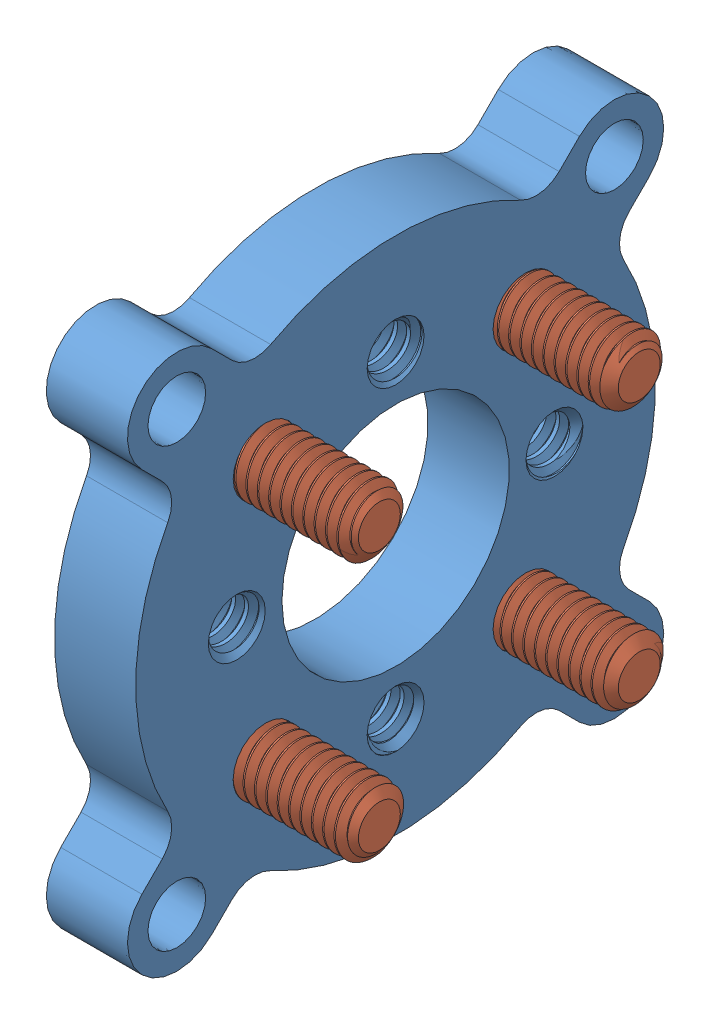
SolidWorks assembly gobilda-to-actobotics-bracket-1206-0016-0004, configuration Default. Lengths in mm.
Overall size (12.17 33.02 33.02).
5 component instances, 2 part files, 0 mates.
Components (placement in the parent):
- 1206-0016-0004-1: 1206-0016-0004 [Default] at (-38.84 3.03 17.1166) size (5.21 33.02 33.02)
- 2800-0004-0008_90128A207-1: 2800-0004-0008_90128A207 [Default] at (-26.84 11.03 25.1166) x (0 0 -1) z (1 0 0) size (7 7 12.17)
- 2800-0004-0008_90128A207-2: 2800-0004-0008_90128A207 [Default] at (-26.84 11.03 9.1166) x (0 -1 0) z (1 0 0) size (7 7 12.17)
- 2800-0004-0008_90128A207-3: 2800-0004-0008_90128A207 [Default] at (-26.84 -4.97 9.1166) x (0 0 1) z (1 0 0) size (7 7 12.17)
- 2800-0004-0008_90128A207-4: 2800-0004-0008_90128A207 [Default] at (-26.84 -4.97 25.1166) x (0 1 0) z (1 0 0) size (7 7 12.17)
